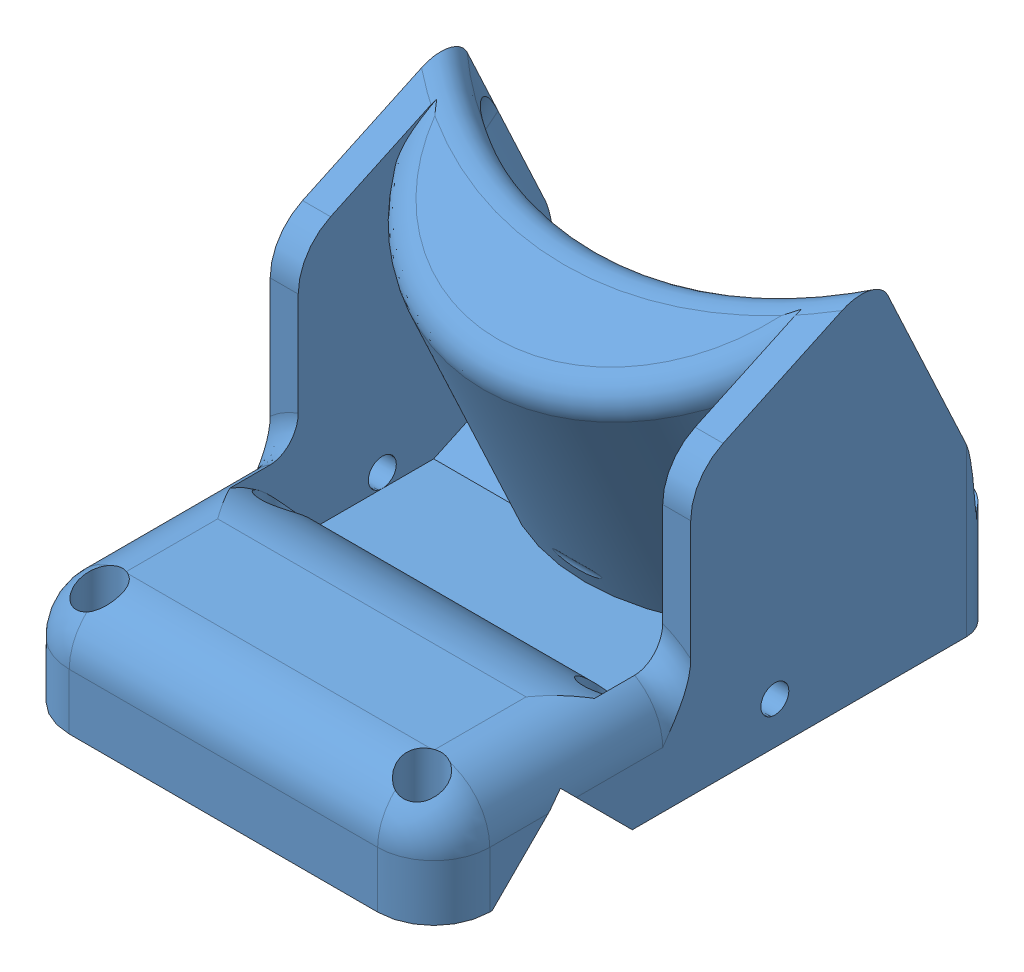
SolidWorks assembly Baugruppe2, configuration Standard. Lengths in mm.
Overall size (76.89 75.96 104.76).
3 component instances, 3 part files, 6 mates.
Components (placement in the parent):
- Zelteingang-1: Zelteingang [Standard] at (-10.9214 -29.8925 100) size (76.89 62.78 100)
- G4 LED-1: G4 LED [Standard] at (-10.9214 8.9831 125.3083) x (1 0 0) z (0 0.906308 0.422618) size (30 9.9 34.79)
- G4 Sockel-1: G4 Sockel [Standard] at (-10.9214 -13.9916 115.4226) x (-0.707107 0.298836 -0.640856) z (0 0.906308 0.422618) size (16 16 33.5)
Mates (geometry in assembly coordinates):
- Deckungsgleich1: coincident: plane of Zelteingang-1 through (-10.9214 -13.9916 115.4226) normal (0 0.906308 0.422618); plane of G4 Sockel-1 through (-10.9214 -13.9916 115.4226) normal (0 -0.906308 -0.422618)
- Konzentrisch1: concentric: cylinder of Zelteingang-1 through (-15.164 -3.1355 115.8037) axis (0 -0.906308 -0.422618) radius 1.4; cylinder of G4 Sockel-1 through (-15.164 -12.1986 111.5775) axis (0 0.906308 0.422618) radius 1.5
- Konzentrisch2: concentric anti-aligned: cylinder of Zelteingang-1 through (-6.6787 -6.7215 123.4939) axis (0 -0.906308 -0.422618) radius 1.4; cylinder of G4 Sockel-1 through (-6.6787 -15.7846 119.2678) axis (0 0.906308 0.422618) radius 1.5
- Konzentrisch3: concentric: cylinder of G4 LED-1 through (-13.4214 -2.468 120.7962) axis (0 -0.906308 -0.422618) radius 0.75; cylinder of G4 Sockel-1 through (-13.4214 -13.9916 115.4226) axis (0 0.906308 0.422618) radius 0.75
- Konzentrisch4: concentric: cylinder of G4 LED-1 through (-8.4214 -2.468 120.7962) axis (0 -0.906308 -0.422618) radius 0.75; cylinder of G4 Sockel-1 through (-8.4214 -13.9916 115.4226) axis (0 0.906308 0.422618) radius 0.75
- Tangential1: tangent anti-aligned: cylinder of G4 LED-1 through (-10.9214 9.5747 124.0395) axis (0 -0.422618 0.906308) radius 15; plane of G4 Sockel-1 through (-10.9214 -4.9285 119.6488) normal (0 0.906308 0.422618)
